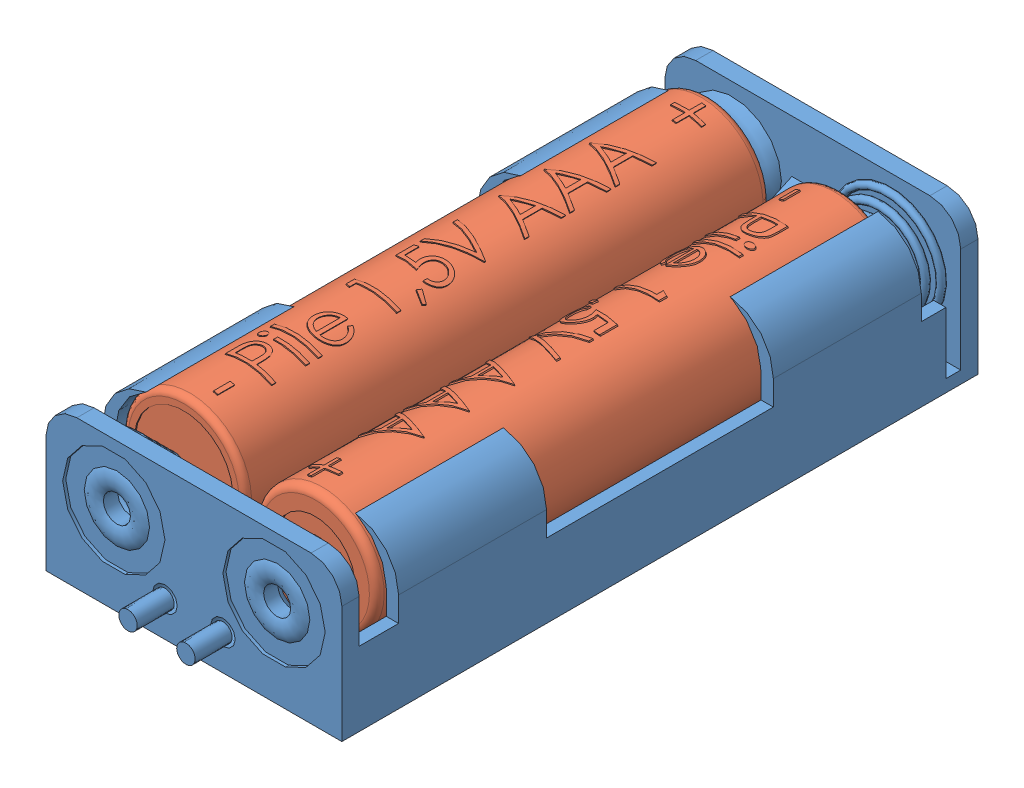
SolidWorks assembly Coupleur + 2xAAA, configuration Default. Lengths in mm.
Overall size (25.73 14.75 54.6).
3 component instances, 2 part files, 6 mates.
Components (placement in the parent):
- Coupleur 2xAAA-1: Coupleur 2xAAA [Défaut] at origin size (24 12 54.6)
- Pile 1,5V LR3 AAA-1: Pile 1,5V LR3 AAA [Défaut] at (-18 7.6699 44.934) x (0 0 -1) z (0.453786 0.891111 0) size (44.1 10 10.1)
- Pile 1,5V LR3 AAA-2: Pile 1,5V LR3 AAA [Défaut] at (-6 7.6699 3.866) x (0 0 1) z (-0.602723 0.79795 0) size (44.1 10 10.1)
Mates (geometry in assembly coordinates):
- Tangent4: tangent: line of Coupleur 2xAAA-1 through (-20.5 12 15.2) axis (0 0 -1); cylinder of Pile 1,5V LR3 AAA-1 through (-18 7.6699 0.934) axis (0 0 -1) radius 5
- Tangent2: tangent: plane of Coupleur 2xAAA-1 through (-23 8 48.8) normal (1 0 0); cylinder of Pile 1,5V LR3 AAA-1 through (-18 7.6699 0.934) axis (0 0 -1) radius 5
- Tangent3: tangent: face of Coupleur 2xAAA-1; plane of Pile 1,5V LR3 AAA-1 through (-19.1139 8.2371 0.934) normal (0 0 -1)
- Tangent8: tangent: line of Coupleur 2xAAA-1 through (-3.5 12 15.2) axis (0 0 -1); cylinder of Pile 1,5V LR3 AAA-2 through (-6 7.6699 47.866) axis (0 0 1) radius 5
- Tangent9: tangent: plane of Coupleur 2xAAA-1 through (-1 1 48.8) normal (-1 0 0); cylinder of Pile 1,5V LR3 AAA-2 through (-6 7.6699 47.866) axis (0 0 1) radius 5
- Tangent10: tangent: face of Coupleur 2xAAA-1; plane of Pile 1,5V LR3 AAA-2 through (-5.0026 8.4233 47.866) normal (0 0 1)
